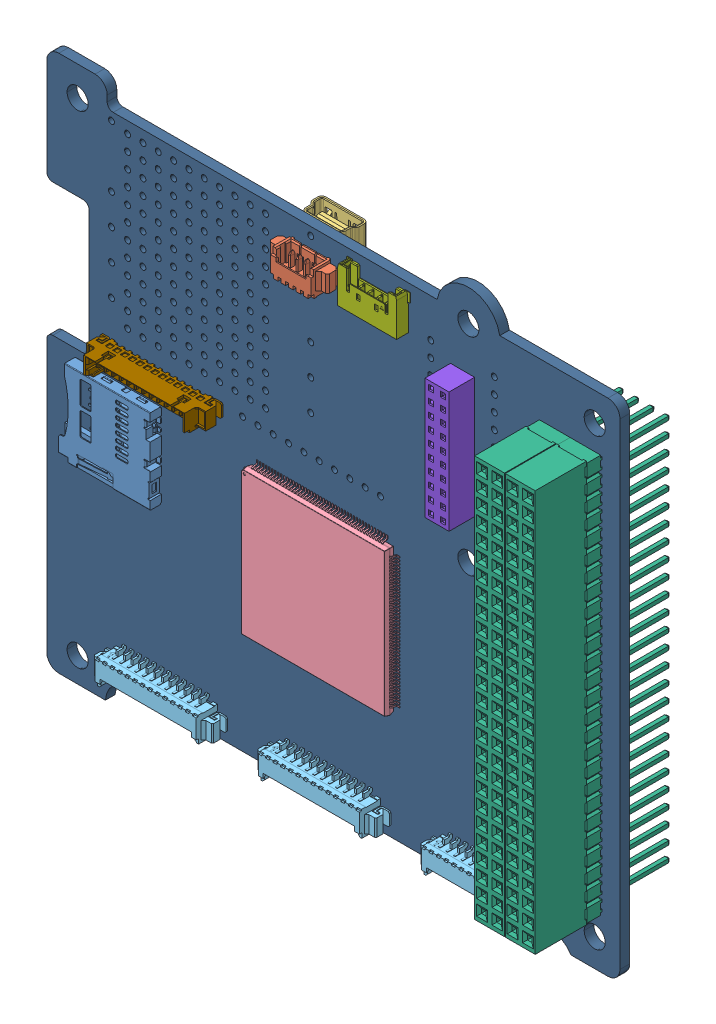
SolidWorks assembly OBC_EnduroSat, configuration Default. Lengths in mm.
Overall size (95 89.38 23.24).
36 component instances, 10 part files, 0 mates.
Components (placement in the parent):
- OBC_EnduroSat.STEP-1: OBC_EnduroSat.STEP [Default] at origin size (95 89.38 23.24)
  - SD1021117.STEP-1: SD1021117.STEP [Default] at origin size (15.2 14.1 1.88)
    - User_Library-473521001_microSD.STEP-1: User_Library-473521001_microSD.STEP [Default] at (11.4631 39.834 0.9) x (0 -1 0) z (0 0 1) size (14.1 15.2 1.88)
  - P1021117.STEP-1: P1021117.STEP [Default] at origin size (10.15 5.2 3.4)
    - MOLEX_Pico_Blade_532610471.STEP-1: MOLEX_Pico_Blade_532610471.STEP [Default] at (43.8404 79.9325 1.7) size (10.15 5.2 3.4)
      - Open CASCADE STEP translator 6.8 1.14.1.1.STEP-1: Open CASCADE STEP translator 6.8 1.14.1.1.STEP [Default] at origin size (10.15 5.2 3.4)
  - USB1021117.STEP-1: USB1021117.STEP [Default] at origin size (9.9 9.22 5.09)
    - USB_Mini_B_SMT_Horisontal.STEP-1: USB_Mini_B_SMT_Horisontal.STEP [Default] at (43.8628 84.9308 -3.6122) x (1 0 0) z (0 1 0) size (9.9 5.09 9.22)
  - U1021117.STEP-1: U1021117.STEP [Default] at origin size (25.77 25.77 1.57)
    - User_Library-LQFP176-0_5.STEP-1: User_Library-LQFP176-0_5.STEP [Default] at (45.653 34.1752 0.75) x (1 0 0) z (0 0 1) size (25.77 25.77 1.57)
  - PAN6021117.STEP-1: PAN6021117.STEP [Default] at origin size (20.15 5.2 3.5)
    - MOLEX_Pico_Blade_532611271.STEP-1: MOLEX_Pico_Blade_532611271.STEP [Default] at (74.0242 8.708 -1.6) x (-1 0 0) z (0 0 -1) size (20.15 5.2 3.5)
  - PAN5021117.STEP-1: PAN5021117.STEP [Default] at origin size (20.15 5.2 3.5)
    - MOLEX_Pico_Blade_532611271.STEP-1: MOLEX_Pico_Blade_532611271.STEP [Default] at (46.9392 8.708 -1.6) x (-1 0 0) z (0 0 -1) size (20.15 5.2 3.5)
  - PAN4021117.STEP-1: PAN4021117.STEP [Default] at origin size (20.15 5.2 3.5)
    - MOLEX_Pico_Blade_532611271.STEP-1: MOLEX_Pico_Blade_532611271.STEP [Default] at (19.8882 8.708 -1.6) x (-1 0 0) z (0 0 -1) size (20.15 5.2 3.5)
  - PAN3021117.STEP-1: PAN3021117.STEP [Default] at origin size (20.15 5.2 3.5)
    - MOLEX_Pico_Blade_532611271.STEP-1: MOLEX_Pico_Blade_532611271.STEP [Default] at (73.9902 8.708 0) x (1 0 0) z (0 0 1) size (20.15 5.2 3.5)
  - PAN2021117.STEP-1: PAN2021117.STEP [Default] at origin size (20.15 5.2 3.5)
    - MOLEX_Pico_Blade_532611271.STEP-1: MOLEX_Pico_Blade_532611271.STEP [Default] at (46.9392 8.708 0) size (20.15 5.2 3.5)
  - PAN1021117.STEP-1: PAN1021117.STEP [Default] at origin size (20.15 5.2 3.5)
    - MOLEX_Pico_Blade_532611271.STEP-1: MOLEX_Pico_Blade_532611271.STEP [Default] at (19.8882 8.708 0) size (20.15 5.2 3.5)
  - H2021117.STEP-1: H2021117.STEP [Default] at origin size (5.08 66.55 23.24)
    - Samtec-ESQ-126-14-G-D.STEP-1: Samtec-ESQ-126-14-G-D.STEP [Default] at (89.5246 43.45 2.5522) x (-1 0 0) z (0 1 0) size (5.08 23.24 66.55)
  - H1021117.STEP-1: H1021117.STEP [Default] at origin size (5.08 66.55 23.24)
    - Samtec-ESQ-126-14-G-D.STEP-1: Samtec-ESQ-126-14-G-D.STEP [Default] at (84.4446 43.45 2.5522) x (-1 0 0) z (0 1 0) size (5.08 23.24 66.55)
  - J1021117.STEP-1: J1021117.STEP [Default] at origin size (10.55 6.44 2)
    - 5040500491.STEP-1: 5040500491.STEP [Default] at (55.0672 77.863 1) x (1 0 0) z (0 0 1) size (10.55 6.44 2)
      - Open CASCADE STEP translator 6.8 1.245.1.1.STEP-1: Open CASCADE STEP translator 6.8 1.245.1.1.STEP [Default] at origin size (10.55 6.44 2)
  - JP2021117.STEP-1: JP2021117.STEP [Default] at origin size (5.56 20 4.5)
    - Samtec-TLE-110-01-G-DV.STEP-1: Samtec-TLE-110-01-G-DV.STEP [Default] at (68.9102 66.945 2.0874) x (0 1 0) z (1 0 0) size (20 4.5 5.56)
  - JP14021117.STEP-1: JP14021117.STEP [Default] at origin size (5.56 20 4.5)
    - Samtec-TLE-110-01-G-DV.STEP-1: Samtec-TLE-110-01-G-DV.STEP [Default] at (68.8848 66.945 -3.6873) x (0 1 0) z (-1 0 0) size (20 4.5 5.56)
  - JP15021117.STEP-1: JP15021117.STEP [Default] at origin size (20.15 4.2 4.7)
    - User_Library-molex_53398_1271.STEP-1: User_Library-molex_53398_1271.STEP [Default] at (19.1599 50.8269 0) x (1 0 0) z (0 0 1) size (20.15 4.2 4.7)
  - Board021117.STEP-1: Board021117.STEP [Default] at origin size (95 89.38 1.6)
